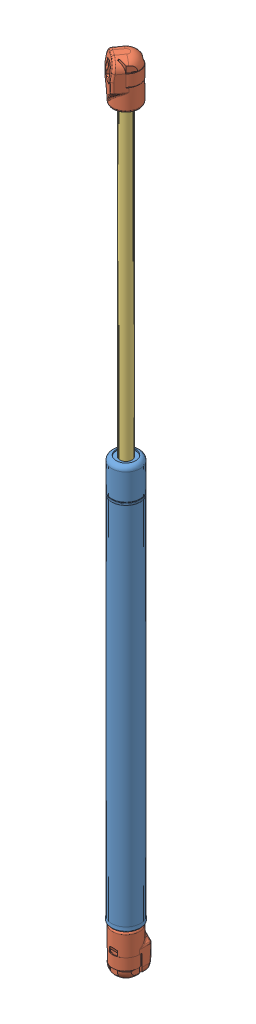
SolidWorks assembly strut_assem, configuration Default. Lengths in mm.
Overall size (24.82 520.7 25.05).
4 component instances, 3 part files, 7 mates.
Components (placement in the parent):
- base-1: base [Default] at (0.5379 24.5591 241.1284) size (19.09 263.52 19.09)
- end_mounts-1: end_mounts [Default] at (0.5379 24.5591 241.1284) x (0 0 -1) z (-1 0 0) size (18.36 29 17.4)
- end_mounts-2: end_mounts [Default] at (0.5379 487.2591 241.1284) x (-0.579382 0 0.815056) z (-0.815056 0 -0.579382) size (18.36 29 17.4)
- Part1^strut_assem-1: Part1^strut_assem [Default] at (0.5379 287.2341 241.1284) x (0.613896 0 -0.789387) z (0 1 0) size (7.9 7.9 200.03) (virtual)
Mates (geometry in assembly coordinates):
- Coincident1: coincident: plane of base-1 through (9.5386 24.5591 241.1284) normal (0 -1 0); plane of end_mounts-1 through (0.5379 24.5591 241.1284) normal (0 1 0)
- Concentric1: concentric: cylinder of base-1 through (0.5379 24.5591 241.1284) axis (0 -1 0) radius 9.34; cylinder of end_mounts-1 through (0.5379 -4.4409 241.1284) axis (0 1 0) radius 8.7
- Parallel1: parallel: plane of end_mounts-1 through (2.7379 2.0591 232.4284) normal (0 0 -1); plane of assembly through (0 0 0) normal (0 0 1)
- Concentric2: concentric: cylinder of base-1 through (0.5379 24.5591 241.1284) axis (0 -1 0) radius 9.34; cylinder of end_mounts-2 through (0.5379 516.2591 241.1284) axis (0 -1 0) radius 8.7
- Coincident6: coincident: plane of end_mounts-2 through (0.5379 487.2591 241.1284) normal (0 -1 0); plane of Part1^strut_assem-1 through (0.5379 487.2591 241.1284) normal (0 1 0)
- Concentric3: concentric: cylinder of base-1 through (0.5379 24.5591 241.1284) axis (0 -1 0) radius 9.34; cylinder of Part1^strut_assem-1 through (0.5379 487.2591 241.1284) axis (0 -1 0) radius 3.95
- LimitDistance1: limit distance = 200.025 mm: plane of end_mounts-2 through (0.5379 487.2591 241.1284) normal (0 -1 0); plane of base-1 through (0.5379 287.2341 241.1284) normal (0 1 0)
